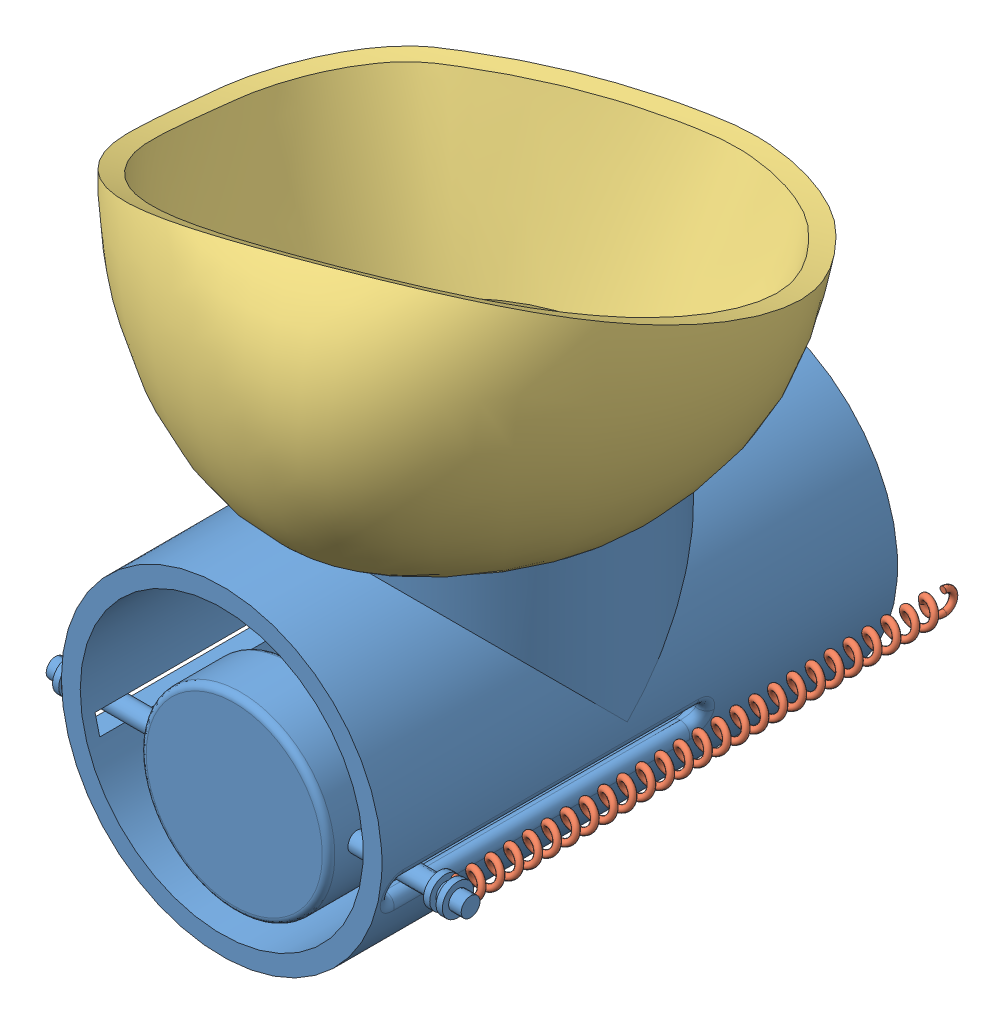
SolidWorks assembly spring assembly to the cylinder_11.06pm, configuration Default. Lengths in mm.
Overall size (116.81 106.15 115.05).
4 component instances, 3 part files, 6 mates.
Components (placement in the parent):
- bottom part-1: bottom part [Default] at (16.4612 51.9827 29.7161) size (66 51.5 82)
- spring-1: spring [Default] at (46.4612 46.5132 103.532) x (0 0.999821 0.018905) z (-1 0 0) size (5.47 82.4 5.47)
- spring-3: spring [Default] at (-13.5388 46.4913 103.5318) x (0 -0.999986 -0.005211) z (1 0 0) size (5.47 82.4 5.47)
- funnel-1: funnel [Default] at (16.4612 127.9827 72.7161) x (0.358061 0 0.933698) z (0.933698 0 -0.358061) size (88.22 55.15 91.27)
Mates (geometry in assembly coordinates):
- Concentric1: concentric: cylinder of bottom part-1 through (-16.5388 46.483 105.1317) axis (1 0 0) radius 1.5; circle of spring-1
- Concentric2: concentric: circle of bottom part-1; circle of spring-1
- Coincident1: coincident: plane of bottom part-1 through (46.4612 46.483 105.1317) normal (-1 0 0); circle of spring-1
- Concentric4: concentric: cylinder of bottom part-1 through (-16.5388 46.483 105.1317) axis (1 0 0) radius 1.5; circle of spring-3
- Coincident2: coincident: plane of bottom part-1 through (-13.5388 46.483 105.1317) normal (1 0 0); circle of spring-3
- Coincident3: coincident: circle of bottom part-1; circle of funnel-1
